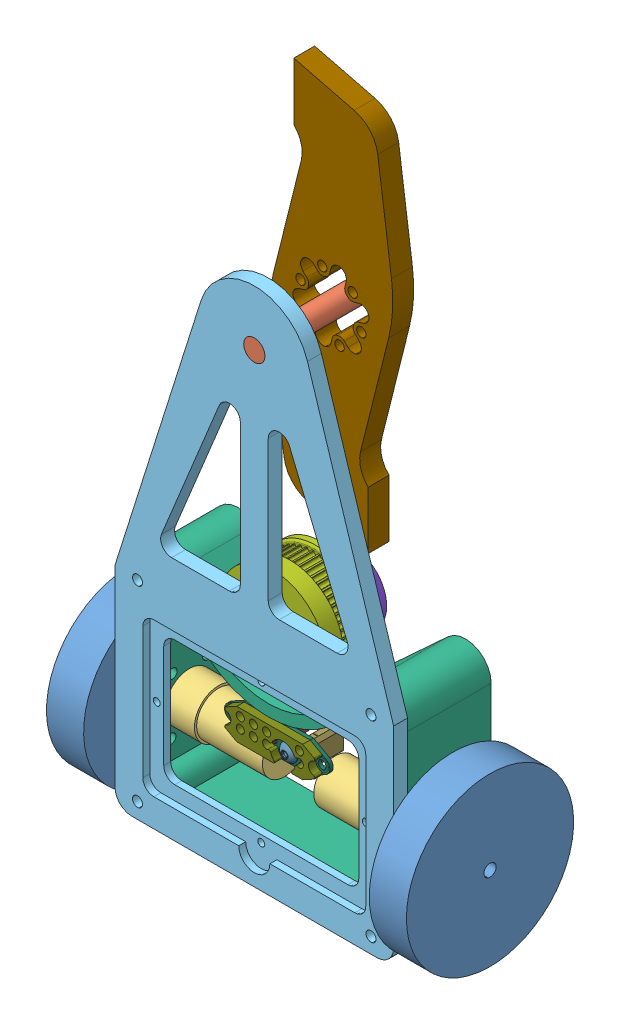
SolidWorks assembly origanal combat bot TPU, configuration Default. Lengths in mm.
Overall size (164.04 315.38 98.18).
30 component instances, 18 part files, 53 mates.
Components (placement in the parent):
- wheel-1: wheel [Default] at (-128.5875 34.925 25.4) x (-1 0 0) z (0 -0.935756 -0.352647) size (16.93 76.2 76.2)
- wheel-2: wheel [Default] at (1.5875 34.925 25.4) x (1 0 0) z (0 -0.978759 -0.205012) size (16.93 76.2 76.2)
- pin-1: pin [Default] at (-62.5126 210.1871 0) x (-0.607765 0.794117 0) z (0.794117 0.607765 0) size (9.65 50.8 9.65)
- 2030 4500kv with gearbox v2-1: 2030 4500kv with gearbox v2 [Default] at (-8.3063 27.0331 25.5745) x (0 -0.022102 -0.999756) z (0 -0.999756 0.022102) size (22 71.4 22)
- 22mm Motor Mount V1 v1-1: 22mm Motor Mount V1 v1 [Default] at (1.5875 34.925 25.4) x (0 -0.999756 0.022102) z (-1 0 0) size (34.92 25.4 1.59)
- 22mm Motor Mount V1 v1-2: 22mm Motor Mount V1 v1 [Default] at (-128.5875 34.925 25.4) x (0 0.999756 -0.022102) z (1 0 0) size (34.92 25.4 1.59)
- 2030 4500kv with gearbox v2-2: 2030 4500kv with gearbox v2 [Default] at (-118.6937 42.8169 25.2255) x (0 -0.022102 -0.999756) z (0 0.999756 -0.022102) size (22 71.4 22)
- Top plate-1: Top plate [Default] at (-63.5 47.625 44.45) x (0 -1 0) z (-1 0 0) size (237.29 6.35 127)
- Top cover-1: Top cover [Default] at (-63.5 47.625 47.625) x (-1 0 0) z (0 1 0) size (101.6 3.3 69.85)
- Bottom Plate-6: Bottom Plate [Default] at (-63.5 47.625 0) x (0 -1 0) z (-1 0 0) size (237.29 6.35 127)
- TPU Body-1: TPU Body [Default] at (-136.525 66.675 6.35) x (0 -1 0) z (-1 0 0) size (101.6 38.1 127)
- 48tooth pully_3530 motor combo-1: 48tooth pully_3530 motor combo [Default] at (-63.5 96.5708 5.35) x (0 0 1) z (0 1 0) size (36 48.63 48.63)
  - 48tooth pully_3530 motor combo.step-1: 48tooth pully_3530 motor combo.step [Default] at origin size (36 48.63 48.63)
    - 3mm 48tooth GT2 Printable v2.step-1: 3mm 48tooth GT2 Printable v2.step [Default] at (23.364 0 0) x (0 1 0) z (0 0 1) size (48.63 22.27 48.63)
    - Motor_3536.step-1: Motor_3536.step [Default] at origin size (36 35 35)
- bar weapon.STEP-1: bar weapon.STEP [Default] at (-63.5 211.8868 6.35) x (-0.970143 0.242536 0) z (0 0 1) size (76.2 165.1 9.53)
- 91115A203_Female Threaded Hex Standoff-1: 91115A203_Female Threaded Hex Standoff [91115A203] at (-116.7002 94.5146 25.4) x (-0.5 -0.866025 0) z (0 0 -1) size (7.14 6.35 38.41)
- 91115A203_Female Threaded Hex Standoff-2: 91115A203_Female Threaded Hex Standoff [91115A203] at (-10.3199 94.5146 25.4) x (-0.5 -0.866025 0) z (0 0 -1) size (7.14 6.35 38.41)
- 91115A203_Female Threaded Hex Standoff-3: 91115A203_Female Threaded Hex Standoff [91115A203] at (-116.7204 7.0854 25.4) x (-0.5 -0.866025 0) z (0 0 -1) size (7.14 6.35 38.41)
- 91115A203_Female Threaded Hex Standoff-4: 91115A203_Female Threaded Hex Standoff [91115A203] at (-10.3098 7.068 25.4) x (-1 0 0) z (0 0 -1) size (7.14 6.35 38.41)
- just cuz_SwitchBoard-1: just cuz_SwitchBoard [Default] at (-56.8286 51.9533 41.05) size (48 14 17.55)
  - just cuz_SwitchBoard.stp-1: just cuz_SwitchBoard.stp [Default] at origin size (48 14 17.55)
    - XT30_Female.stp-1: XT30_Female.stp [Default] at (-4.7913 -1.9356 -6.5462) x (-1 0 0) z (0 0 -1) size (5.25 10.45 15.6)
    - XT30_Male.stp-1: XT30_Male.stp [Default] at (4.8749 -1.9112 -14.0462) size (5.25 10.45 15.5)
    - 8-32 PEM Nut Insert.stp-1: 8-32 PEM Nut Insert.stp [Default] at (0 0 -4.0856) x (1 0 0) z (0 -1 0) size (8.64 3.94 8.64)
    - XT30_Female.stp-2: XT30_Female.stp [Default] at (-10.7913 -1.9356 -6.5462) x (-1 0 0) z (0 0 -1) size (5.25 10.45 15.6)
    - XT30_Female.stp-3: XT30_Female.stp [Default] at (-16.7913 -1.9356 -6.5462) x (-1 0 0) z (0 0 -1) size (5.25 10.45 15.6)
    - 8-32 3-16 NO THREADS_ Button Head Hex Drive Screw.stp-1: 8-32 3-16 NO THREADS_ Button Head Hex Drive Screw.stp [Default] at (0 0 -0.7667) x (-1 0 0) z (0 0 1) size (7.92 7.92 6.97)
    - Switch PD Board V1.3 Bottom Connectors.stp-1: Switch PD Board V1.3 Bottom Connectors.stp [Default] at origin size (48 14 1.56)
    - Switch PD Board V1.3 Bottom Connectors-0.stp-1: Switch PD Board V1.3 Bottom Connectors-0.stp [Default] at origin size (41 14 3.4)
Mates (geometry in assembly coordinates):
- Concentric19: concentric anti-aligned: cylinder of wheel-1 through (-128.5875 34.925 25.4) axis (-1 0 0) radius 2.794; cylinder of 2030 4500kv with gearbox v2-1 through (-0.4125 34.925 25.4) axis (1 0 0) radius 3
- Parallel5: parallel anti-aligned: cylinder of wheel-2 through (1.5875 34.925 25.4) axis (1 0 0) radius 2.794; cylinder of 2030 4500kv with gearbox v2-2 through (-126.5875 34.925 25.4) axis (-1 0 0) radius 3
- Parallel14: parallel anti-aligned: plane of 2030 4500kv with gearbox v2-1 through (-0.4125 31.1877 19.4812) normal (0 -0.022102 -0.999756); plane of 22mm Motor Mount V1 v1-1 through (1.5875 31.1539 19.3684) normal (0 0.022102 0.999756)
- Concentric39: concentric anti-aligned: cylinder of 2030 4500kv with gearbox v2-1 through (-0.4125 34.925 25.4) axis (1 0 0) radius 7; cylinder of 22mm Motor Mount V1 v1-1 through (1.5875 34.925 25.4) axis (-1 0 0) radius 7.1135
- Concentric54: concentric aligned: cylinder of 22mm Motor Mount V1 v1-2 through (-128.5875 41.4281 31.6218) axis (1 0 0) radius 1.2; cylinder of 2030 4500kv with gearbox v2-2 through (-126.5875 41.4281 31.6218) axis (1 0 0) radius 1
- Concentric55: concentric aligned: cylinder of 22mm Motor Mount V1 v1-2 through (-128.5875 28.4219 19.1782) axis (1 0 0) radius 1.2; cylinder of 2030 4500kv with gearbox v2-2 through (-126.5875 28.4219 19.1782) axis (1 0 0) radius 1
- Coincident67: coincident anti-aligned: plane of Top plate-1 through (-12.7 12.7 47.625) normal (-1 0 0); plane of Top cover-1 through (-12.7 82.55 50.927) normal (1 0 0)
- Coincident68: coincident anti-aligned: plane of Top plate-1 through (-12.7 82.55 47.625) normal (0 -1 0); plane of Top cover-1 through (-12.7 82.55 50.927) normal (0 1 0)
- Coincident69: coincident anti-aligned: plane of Top plate-1 through (-63.5 47.625 47.625) normal (0 0 1); plane of Top cover-1 through (-63.5 47.625 47.625) normal (0 0 -1)
- Coincident78: coincident aligned: plane of 22mm Motor Mount V1 v1-2 through (-128.5875 34.925 25.4) normal (-1 0 0); plane of 2030 4500kv with gearbox v2-2 through (-128.5875 34.925 25.4) normal (-1 0 0)
- Concentric74: concentric anti-aligned: cylinder of pin-1 through (-63.5 211.8868 50.8) axis (0 0 -1) radius 4.826; cylinder of Top plate-1 through (-63.5 211.8868 44.45) axis (0 0 1) radius 4.826
- Coincident99: coincident anti-aligned: plane of Top plate-1 through (-63.5 47.625 44.45) normal (0 0 -1); plane of TPU Body-1 through (-136.525 66.675 44.45) normal (0 0 1)
- Coincident100: coincident aligned: plane of Bottom Plate-6 through (-127 0 6.35) normal (0 -1 0); plane of TPU Body-1 through (-127 0 44.45) normal (0 -1 0)
- Coincident101: coincident aligned: plane of Top plate-1 through (-127 95.25 50.8) normal (-1 0 0); plane of TPU Body-1 through (-127 95.25 44.45) normal (-1 0 0)
- Coincident102: coincident anti-aligned: plane of Bottom Plate-6 through (-63.5 47.625 6.35) normal (0 0 1); plane of TPU Body-1 through (-136.525 66.675 6.35) normal (0 0 -1)
- Coincident103: coincident aligned: plane of Top plate-1 through (-127 0 50.8) normal (0 -1 0); plane of TPU Body-1 through (-127 0 44.45) normal (0 -1 0)
- Coincident104: coincident aligned: plane of Bottom Plate-6 through (-127 95.25 6.35) normal (-1 0 0); plane of TPU Body-1 through (-127 95.25 44.45) normal (-1 0 0)
- Coincident105: coincident aligned: plane of pin-1 through (-63.5 211.8868 50.8) normal (0 0 1); plane of Top plate-1 through (-63.5 47.625 50.8) normal (0 0 1)
- Coincident106: coincident anti-aligned: plane of TPU Body-1 through (-127 0 44.45) normal (0 -1 0)
- Concentric75: concentric anti-aligned: cylinder of wheel-2 through (1.5875 34.925 25.4) axis (1 0 0) radius 2.794; cylinder of 2030 4500kv with gearbox v2-2 through (-126.5875 34.925 25.4) axis (-1 0 0) radius 3
- Coincident125: coincident anti-aligned: plane of Bottom Plate-6 through (-63.5 47.625 0) normal (0 0 -1)
- Coincident126: coincident aligned: plane of TPU Body-1 through (0 6.35 -120.8087) normal (1 0 0)
- Coincident127: coincident anti-aligned: plane of TPU Body-1 through (-127 0 44.45) normal (0 -1 0)
- Coincident129: coincident anti-aligned: plane of 22mm Motor Mount V1 v1-1 through (0 34.925 25.4) normal (-1 0 0); plane of TPU Body-1 through (0 6.35 -120.8087) normal (1 0 0)
- Coincident132: coincident anti-aligned: plane of 22mm Motor Mount V1 v1-2 through (-127 34.925 25.4) normal (1 0 0); plane of TPU Body-1 through (-127 95.25 44.45) normal (-1 0 0)
- Coincident133: coincident aligned: plane of 2030 4500kv with gearbox v2-1 through (1.5875 34.925 25.4) normal (1 0 0); plane of 22mm Motor Mount V1 v1-1 through (1.5875 34.925 25.4) normal (1 0 0)
- Coincident137: coincident anti-aligned: plane of wheel-2 through (1.5875 34.925 25.4) normal (-1 0 0); plane of 22mm Motor Mount V1 v1-1 through (1.5875 34.925 25.4) normal (1 0 0)
- Coincident138: coincident anti-aligned: plane of wheel-1 through (-128.5875 34.925 25.4) normal (1 0 0); plane of 22mm Motor Mount V1 v1-2 through (-128.5875 34.925 25.4) normal (-1 0 0)
- Coincident140: coincident anti-aligned: plane of Bottom Plate-6 through (-63.5 47.625 6.35) normal (0 0 1); plane of 48tooth pully_3530 motor combo-1/48tooth pully_3530 motor combo.step-1/Motor_3536.step-1 through (-63.5 80.6958 6.35) normal (0 0 -1)
- Concentric94: concentric anti-aligned: circle of Bottom Plate-6; circle of 48tooth pully_3530 motor combo-1/48tooth pully_3530 motor combo.step-1/Motor_3536.step-1
- Concentric98: concentric anti-aligned: cylinder of 2030 4500kv with gearbox v2-1 through (-0.4125 34.925 25.4) axis (-1 0 0) radius 11; cylinder of TPU Body-1 through (-127 34.925 25.4) axis (1 0 0) radius 11
- Concentric99: concentric anti-aligned: cylinder of 22mm Motor Mount V1 v1-1 through (1.5875 22.0527 17.7451) axis (-1 0 0) radius 2.1526; cylinder of TPU Body-1 through (-127 22.0527 17.7451) axis (1 0 0) radius 2.1526
- Concentric100: concentric aligned: cylinder of 2030 4500kv with gearbox v2-2 through (-126.5875 34.925 25.4) axis (1 0 0) radius 11; cylinder of TPU Body-1 through (-127 34.925 25.4) axis (1 0 0) radius 11
- Concentric101: concentric aligned: cylinder of 22mm Motor Mount V1 v1-2 through (-128.5875 22.0527 17.7451) axis (1 0 0) radius 2.1526; cylinder of TPU Body-1 through (-127 22.0527 17.7451) axis (1 0 0) radius 2.1526
- Parallel15: parallel anti-aligned: plane of 48tooth pully_3530 motor combo-1/48tooth pully_3530 motor combo.step-1/Motor_3536.step-1 through (-63.5 96.5708 5.35) normal (0 -1 0)
- Coincident141: coincident anti-aligned: plane of Bottom Plate-6 through (-63.5 47.625 6.35) normal (0 0 1); plane of bar weapon.STEP-1 through (-27.8518 196.0102 6.35) normal (0 0 -1)
- Coincident142: coincident anti-aligned: cylinder of pin-1 through (-63.5 211.8868 50.8) axis (0 0 -1) radius 4.826; circle of bar weapon.STEP-1
- Coincident143: coincident anti-aligned: plane of Bottom Plate-6 through (-63.5 47.625 6.35) normal (0 0 1); plane of 91115A203_Female Threaded Hex Standoff-1 through (-116.7002 94.5146 6.35) normal (0 0 -1)
- Coincident144: coincident anti-aligned: plane of TPU Body-1 through (-118.5333 97.6896 6.35) normal (0.866025 -0.5 0); plane of 91115A203_Female Threaded Hex Standoff-1 through (-120.3664 94.5146 44.45) normal (-0.866025 0.5 0)
- Coincident145: coincident anti-aligned: plane of TPU Body-1 through (-114.8873 97.6896 6.35) normal (0 -1 0); plane of 91115A203_Female Threaded Hex Standoff-1 through (-118.5333 97.6896 44.45) normal (0 1 0)
- Coincident156: coincident anti-aligned: plane of Bottom Plate-6 through (-63.5 47.625 6.35) normal (0 0 1); plane of 91115A203_Female Threaded Hex Standoff-3 through (-116.7204 7.0854 6.35) normal (0 0 -1)
- Coincident157: coincident anti-aligned: plane of TPU Body-1 through (-113.0642 7.068 6.35) normal (-0.866025 0.5 0); plane of 91115A203_Female Threaded Hex Standoff-3 through (-113.0542 7.0854 44.45) normal (0.866025 -0.5 0)
- Coincident158: coincident anti-aligned: plane of TPU Body-1 through (-114.8873 3.9104 6.35) normal (0 1 0); plane of 91115A203_Female Threaded Hex Standoff-3 through (-114.8873 3.9104 44.45) normal (0 -1 0)
- Coincident159: coincident anti-aligned: plane of Bottom Plate-6 through (-63.5 47.625 6.35) normal (0 0 1); plane of 91115A203_Female Threaded Hex Standoff-4 through (-10.3098 7.068 6.35) normal (0 0 -1)
- Coincident160: coincident anti-aligned: plane of TPU Body-1 through (-8.4667 3.9104 6.35) normal (-0.866025 0.5 0); plane of 91115A203_Female Threaded Hex Standoff-4 through (-6.6436 7.068 44.45) normal (0.866025 -0.5 0)
- Coincident161: coincident anti-aligned: plane of TPU Body-1 through (-6.6436 7.068 6.35) normal (-0.866025 -0.5 0); plane of 91115A203_Female Threaded Hex Standoff-4 through (-8.4767 10.243 44.45) normal (0.866025 0.5 0)
- Coincident162: coincident anti-aligned: plane of Bottom Plate-6 through (-63.5 47.625 6.35) normal (0 0 1); plane of 91115A203_Female Threaded Hex Standoff-2 through (-10.3199 94.5146 6.35) normal (0 0 -1)
- Coincident163: coincident anti-aligned: plane of TPU Body-1 through (-12.1127 97.6896 6.35) normal (0 -1 0); plane of 91115A203_Female Threaded Hex Standoff-2 through (-12.153 97.6896 44.45) normal (0 1 0)
- Coincident164: coincident anti-aligned: plane of TPU Body-1 through (-6.6436 94.532 6.35) normal (-0.866025 0.5 0); plane of 91115A203_Female Threaded Hex Standoff-2 through (-6.6537 94.5146 44.45) normal (0.866025 -0.5 0)
- Parallel18: parallel aligned: plane of Top plate-1 through (-57.15 205.5368 44.45) normal (1 0 0); plane of bar weapon.STEP-1 through (-46.5589 122.5609 15.875) normal (1 0 0)
- Concentric104: concentric: cylinder of Bottom Plate-6 through (-42.3285 53.9533 0) axis (0 0 1) radius 1.83; cylinder of just cuz_SwitchBoard-1/just cuz_SwitchBoard.stp-1/Switch PD Board V1.3 Bottom Connectors.stp-1 through (-42.3285 53.9533 39.514) axis (0 0 1) radius 1.83
- Concentric105: concentric: cylinder of Bottom Plate-6 through (-83.3289 53.9535 0) axis (0 0 1) radius 1.83; cylinder of just cuz_SwitchBoard-1/just cuz_SwitchBoard.stp-1/Switch PD Board V1.3 Bottom Connectors.stp-1 through (-83.3289 53.9535 39.514) axis (0 0 1) radius 1.83
- Coincident166: coincident anti-aligned: plane of Top plate-1 through (-63.5 47.625 44.45) normal (0 0 -1); plane of just cuz_SwitchBoard-1/just cuz_SwitchBoard.stp-1/Switch PD Board V1.3 Bottom Connectors-0.stp-1 through (-62.8286 53.9534 44.45) normal (0 0 1)
